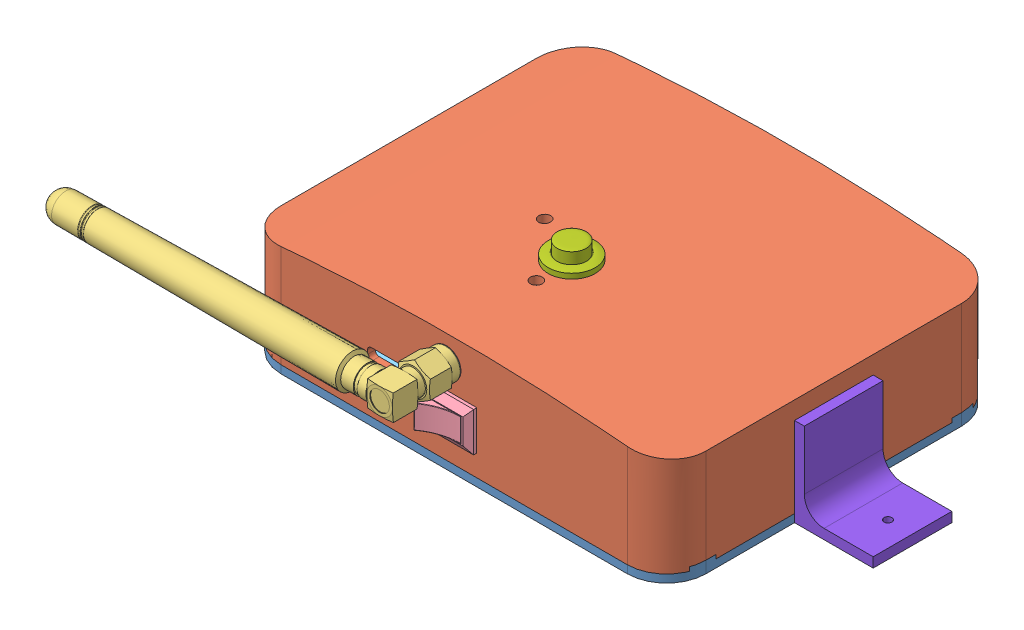
SolidWorks assembly Hub, configuration Default. Lengths in mm.
Overall size (162.63 34.75 103.05).
9 component instances, 8 part files, 22 mates.
Components (placement in the parent):
- Hub_bottom_v2-1: Hub_bottom_v2 [Default] at origin size (108 12.14 85)
- Hub_top_v2-1: Hub_top_v2 [Default] at (0 0 34.0152) size (108 28.27 85)
- Antenna 868  F-1: Antenna 868  F [По умолчанию] at (11.999 23.5 47.7152) x (-0.006213 0.999981 0) z (0 0 1) size (9.24 90.6 18.05)
- Switch on off-1: Switch on off [Default] at (12.24 12.4361 26.0152) x (0 1 0) z (1 0 0) size (10 19.96 15)
- circuit-1: circuit [Default] at (-32.0082 5 27.0118) x (0 0 -1) z (0 1 0) size (72.72 51.79 14.01)
- 18650 Battery Holder v5-1: 18650 Battery Holder v5 [Default] at (28.7632 2 -8.4848) x (1 0 0) z (0 1 0) size (21 75 19.5)
- 18650 Battery Holder v5-2: 18650 Battery Holder v5 [Default] at (49.7632 2 -8.4848) x (1 0 0) z (0 1 0) size (21 75 19.5)
- sw-1: sw [Default] at (11.8847 30.0146 2.0152) x (0.618002 0 -0.786177) z (0 1 0) size (11.94 11.94 27.46)
- Hob_mount-1: Hob_mount [Default] x (1 0 0) z (0 1 0) size (20 20 22.5)
Mates (geometry in assembly coordinates):
- Concentric1: concentric anti-aligned: circle of Hub_top_v2-1; circle of Antenna 868  F-1
- Coincident4: coincident anti-aligned: plane of Hub_top_v2-1 through (0 44 34.0152) normal (0 0 1); plane of Antenna 868  F-1 through (11.999 23.5 34.0152) normal (0 0 -1)
- Coincident5: coincident aligned: plane of Hub_bottom_v2-1 through (-40.001 2 -40.9848) normal (-1 0 0); plane of Hub_top_v2-1 through (-40.001 44 34.0152) normal (-1 0 0)
- Coincident6: coincident aligned: plane of Hub_bottom_v2-1 through (-30.001 2 34.0152) normal (0 0 1); plane of Hub_top_v2-1 through (0 44 34.0152) normal (0 0 1)
- Coincident7: coincident anti-aligned: plane of Hub_top_v2-1 through (0 44 34.0152) normal (0 0 1); plane of Switch on off-1 through (5.42 16.7011 34.0152) normal (0 0 -1)
- Parallel3: parallel anti-aligned: plane of Hub_top_v2-1 through (0 17 19.0152) normal (0 -1 0); plane of Switch on off-1 through (12.24 17.4361 34.0152) normal (0 1 0)
- Parallel4: parallel aligned: plane of Hub_bottom_v2-1 through (-40.001 2 -40.9848) normal (-1 0 0); plane of circuit-1 through (-31.9955 5 27.7611) normal (-1 0 0)
- Coincident9: coincident anti-aligned: plane of Hub_bottom_v2-1 through (-30.001 2 24.0152) normal (0 1 0); plane of 18650 Battery Holder v5-1 through (28.7632 2 -8.4848) normal (0 -1 0)
- Parallel5: parallel aligned: plane of Hub_bottom_v2-1 through (-30.001 2 34.0152) normal (0 0 1); plane of 18650 Battery Holder v5-1 through (18.2632 2 29.0152) normal (0 0 1)
- Coincident10: coincident anti-aligned: plane of 18650 Battery Holder v5-1 through (39.2632 2 29.0152) normal (1 0 0); plane of 18650 Battery Holder v5-2 through (39.2632 2 -45.9848) normal (-1 0 0)
- Coincident11: coincident anti-aligned: plane of Hub_bottom_v2-1 through (-30.001 2 24.0152) normal (0 1 0); plane of 18650 Battery Holder v5-2 through (49.7632 2 -8.4848) normal (0 -1 0)
- Coincident12: coincident aligned: plane of 18650 Battery Holder v5-1 through (39.2632 2 -45.9848) normal (0 0 -1); plane of 18650 Battery Holder v5-2 through (60.2632 2 -45.9848) normal (0 0 -1)
- Width2: width aligned: plane of circuit-1 through (17.9791 5 27.7611) normal (0 0 1); plane of circuit-1 through (-31.9955 5 -44.7307) normal (0 0 -1); plane of Hub_bottom_v2-1 through (-30.001 2 34.0152) normal (0 0 1); plane of Hub_bottom_v2-1 through (-30.001 2 -50.9848) normal (0 0 -1)
- Width3: width aligned: plane of 18650 Battery Holder v5-1 through (18.2632 2 29.0152) normal (0 0 1); plane of 18650 Battery Holder v5-2 through (60.2632 2 -45.9848) normal (0 0 -1); plane of Hub_bottom_v2-1 through (-30.001 2 34.0152) normal (0 0 1); plane of Hub_bottom_v2-1 through (-30.001 2 -50.9848) normal (0 0 -1)
- Parallel6: parallel aligned: plane of Hub_top_v2-1 through (0 2 34.0152) normal (0 -1 0); plane of sw-1 through (11.8847 21.6146 2.0152) normal (0 -1 0)
- Tangent2: tangent: curve of Hub_top_v2-1; plane of sw-1 through (11.8847 30.0146 2.0152) normal (0 -1 0)
- Coincident16: coincident anti-aligned: plane of Hub_bottom_v2-1 through (-30.001 2 24.0152) normal (0 1 0); plane of Hub_top_v2-1 through (0 2 34.0152) normal (0 -1 0)
- Concentric4: concentric aligned: cylinder of Hub_top_v2-1 through (11.8847 44 2.0152) axis (0 -1 0) radius 4.5284; cone of sw-1 through (11.8847 28.4146 2.0152) axis (0 -1 0)
- InPlace1: in place: plane of Hub_bottom_v2-1 through (0 0 0) normal (0 1 0); plane of Hob_mount-1 through (0 0 0) normal (0 1 0); moOrthogonalPlaneRef_w of Hub_bottom_v2-1 through (0 0 0) normal (0 1 0); plane of Hob_mount-1 through (0 0 0) normal (0 0 -1); plane of Hub_bottom_v2-1 through (0 0 0) normal (0 1 0); plane of Hob_mount-1 through (0 0 0) normal (1 0 0); plane of Hub_bottom_v2-1 through (0 0 0) normal (0 1 0); unknown of Hob_mount-1
- Coincident17: coincident aligned: plane of Hub_bottom_v2-1; plane of Hob_mount-1
- Coincident18: coincident aligned: moOrthogonalPlaneRef_w of Hub_bottom_v2-1; plane of Part1^Hub-1 through (0 0 0) normal (0 0 -1)
- Coincident19: coincident anti-aligned: moOrthogonalPlaneRef_w of Hub_bottom_v2-1 through (46.75 -46.75 0) axis (0 0 -1); plane of Part1^Hub-1 through (0 0 0) normal (1 0 0)
